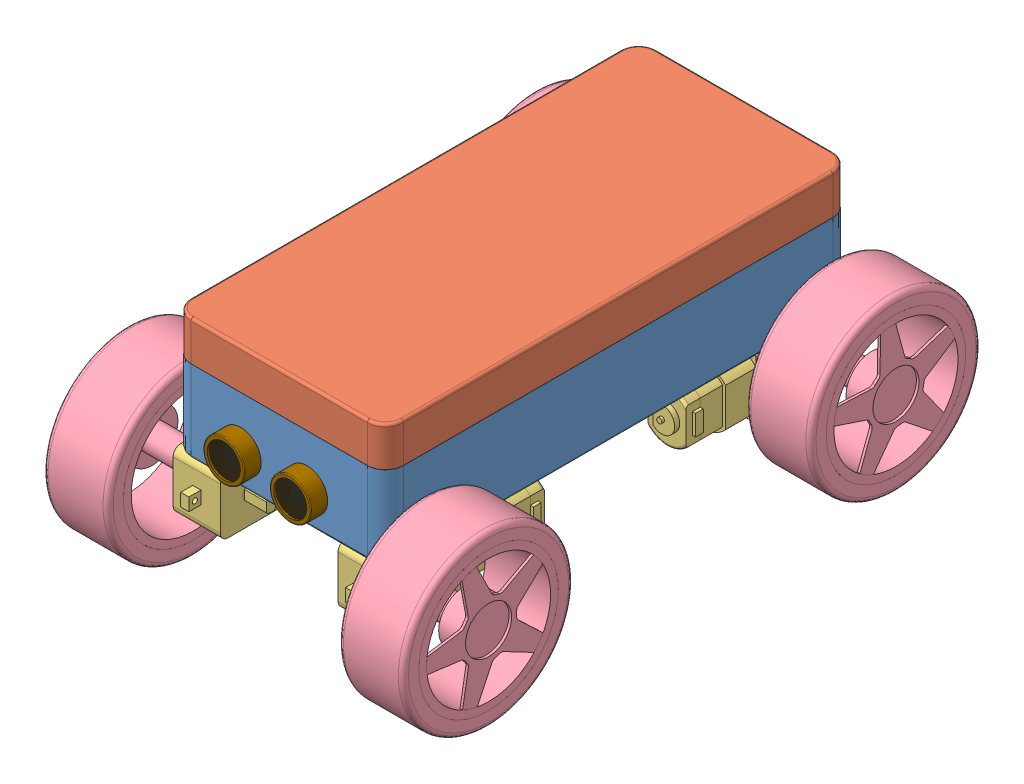
SolidWorks assembly Сборка1, configuration По умолчанию. Lengths in mm.
Overall size (141 100.91 238.58).
16 component instances, 10 part files, 33 mates.
Components (placement in the parent):
- Деталь1-1: Деталь1 [По умолчанию] at origin size (83 32 182)
- Деталь2-1: Деталь2 [По умолчанию] at (0 32.0442 0) x (1 0.000532 0) z (0 0 1) size (83 15.5 182)
- motor-1: motor [Predeterminado] at (-73.75 -11.35 -18.5) x (0 0 1) z (1 0 0) size (71.1 22.7 38)
- llanta-1: llanta [Predeterminado] at (-112 -11.35 -11.35) x (0 -0.972916 0.231159) z (-1 0 0) size (66.5 66.5 29)
- llanta-2: llanta [Predeterminado] at (29 -11.35 -11.35) x (0 0.314264 -0.949335) z (1 0 0) size (66.5 66.5 29)
- motor-2: motor [Predeterminado] at (-9.25 -11.35 -18.5) x (0 0 1) z (-1 0 0) size (71.1 22.7 38)
- motor-3: motor [Predeterminado] at (-9.25 -11.35 -163.5) x (0 0 -1) z (-1 0 0) size (71.1 22.7 38)
- llanta-3: llanta [Predeterminado] at (29 -11.35 -170.65) x (0 0.129067 -0.991636) z (1 0 0) size (66.5 66.5 29)
- motor-4: motor [Predeterminado] at (-73.75 -11.35 -163.5) x (0 0 -1) z (1 0 0) size (71.1 22.7 38)
- llanta-4: llanta [Predeterminado] at (-112 -11.35 -170.65) x (0 -0.02064 -0.999787) z (-1 0 0) size (66.5 66.5 29)
- Деталь3-1: Деталь3 [По умолчанию] at (-2 35 -85) x (0 1 0) z (0 0 1) size (33 61 32)
- Деталь4-1: Деталь4 [По умолчанию] at (-5.6654 2 -180) x (0 -1 0) z (0 0 -1) size (35 60 63)
- arduino-1: arduino [Valor predeterminado] at (-24.2753 10 -74.3614) size (45.18 17 17.78)
- hc05-1: hc05 [Varsayılan] at (-81 18.1 -175.0431) x (0 0 1) z (1 0 0) size (42.6 16.1 5.9)
- Sensor Ultrasonic-1: Sensor Ultrasonic [Predeterminado] at (-43.5678 12.17 -5.37) x (-1 0 0) z (0 0 1) size (45.42 26.14 17.7)
- L298N Dual H Bridge-1: L298N Dual H Bridge [Default] at (-29.5669 3.54 -42.6081) size (43.3 28.21 43.3)
Mates (geometry in assembly coordinates):
- Совпадение1: coincident aligned: line of Деталь1-1 through (-83 32 -175) axis (0 0 1); line of Деталь2-1 through (-83 32 -175) axis (0 0 1)
- Совпадение4: coincident: point of Деталь1-1; point of Деталь2-1
- Концентричный3: concentric anti-aligned: circle of motor-1; circle of llanta-1
- Совпадение5: coincident anti-aligned: plane of motor-1 through (-83 -19.7 -3) normal (-1 0 0); plane of llanta-1 through (-83 -11.35 -11.35) normal (1 0 0)
- Концентричный4: concentric anti-aligned: circle of llanta-2; circle of motor-2
- Совпадение6: coincident anti-aligned: plane of llanta-2 through (0 -11.35 -11.35) normal (-1 0 0); plane of motor-2 through (0 -3 -3) normal (1 0 0)
- Совпадение11: coincident anti-aligned: plane of Деталь1-1 through (-76 0 -7) normal (0 -1 0); plane of motor-2 through (0 0 -37) normal (0 1 0)
- Совпадение13: coincident aligned: plane of Деталь1-1 through (-7 32 0) normal (0 0 1); plane of motor-2 through (0 -19.7 0) normal (0 0 1)
- Совпадение14: coincident aligned: plane of Деталь1-1 through (0 32 -7) normal (1 0 0); plane of motor-2 through (0 -3 -3) normal (1 0 0)
- Совпадение15: coincident aligned: plane of Деталь1-1 through (-7 32 0) normal (0 0 1); plane of motor-1 through (-83 -3 0) normal (0 0 1)
- Совпадение16: coincident aligned: plane of Деталь1-1 through (-83 32 -7) normal (-1 0 0); plane of motor-1 through (-83 -19.7 -3) normal (-1 0 0)
- Совпадение17: coincident anti-aligned: plane of Деталь1-1 through (-76 0 -7) normal (0 -1 0); plane of motor-1 through (-83 0 -37) normal (0 1 0)
- Концентричный5: concentric anti-aligned: circle of motor-3; circle of llanta-3
- Совпадение18: coincident anti-aligned: plane of motor-3 through (0 -19.7 -179) normal (1 0 0); plane of llanta-3 through (0 -11.35 -170.65) normal (-1 0 0)
- Совпадение19: coincident aligned: plane of Деталь1-1 through (-7 32 -182) normal (0 0 -1); plane of motor-3 through (0 -3 -182) normal (0 0 -1)
- Совпадение20: coincident aligned: plane of Деталь1-1 through (0 32 -7) normal (1 0 0); plane of motor-3 through (0 -19.7 -179) normal (1 0 0)
- Совпадение21: coincident anti-aligned: plane of Деталь1-1 through (-76 0 -7) normal (0 -1 0); plane of motor-3 through (0 0 -145) normal (0 1 0)
- Концентричный6: concentric anti-aligned: circle of motor-4; circle of llanta-4
- Совпадение22: coincident anti-aligned: plane of motor-4 through (-83 -3 -179) normal (-1 0 0); plane of llanta-4 through (-83 -11.35 -170.65) normal (1 0 0)
- Совпадение32: coincident aligned: plane of Деталь1-1 through (-7 32 -182) normal (0 0 -1); plane of motor-4 through (-83 -19.7 -182) normal (0 0 -1)
- Совпадение33: coincident aligned: plane of Деталь1-1 through (-83 32 -7) normal (-1 0 0); plane of motor-4 through (-83 -3 -179) normal (-1 0 0)
- Совпадение34: coincident anti-aligned: plane of Деталь1-1 through (-76 0 -7) normal (0 -1 0); plane of motor-4 through (-83 0 -145) normal (0 1 0)
- Совпадение35: coincident anti-aligned: plane of Деталь1-1 through (-7 32 -180) normal (0 0 1); plane of Деталь4-1 through (-65.6654 4 -180) normal (0 0 -1)
- Совпадение36: coincident anti-aligned: plane of Деталь1-1 through (-76 2 -7) normal (0 1 0); plane of Деталь4-1 through (-65.6654 2 -178) normal (0 -1 0)
- Совпадение37: coincident anti-aligned: plane of Деталь3-1 through (-2 7 -112) normal (1 0 0); plane of Деталь1-1 through (-2 32 -7) normal (-1 0 0)
- Совпадение38: coincident anti-aligned: plane of Деталь1-1 through (-76 2 -7) normal (0 1 0); plane of Деталь3-1 through (-63 2 -85) normal (0 -1 0)
- Совпадение39: coincident anti-aligned: plane of Деталь3-1 through (-63 35 -117) normal (0 0 -1); plane of Деталь4-1 through (-65.6654 4 -117) normal (0 0 1)
- Совпадение40: coincident anti-aligned: plane of Деталь1-1 through (-7 32 -2) normal (0 0 -1); plane of Sensor Ultrasonic-1 through (-46.9778 4.05 -2) normal (0 0 1)
- Совпадение41: coincident anti-aligned: plane of Деталь1-1 through (-76 2 -7) normal (0 1 0); plane of Sensor Ultrasonic-1 through (-20.8578 2 -6.97) normal (0 -1 0)
- Совпадение42: coincident anti-aligned: plane of Деталь1-1 through (-76 2 -7) normal (0 1 0); plane of arduino-1 through (11.4947 2 -74.3614) normal (0 -1 0)
- Совпадение43: coincident anti-aligned: plane of Деталь1-1 through (-81 32 -7) normal (1 0 0); plane of hc05-1 through (-81 18.1 -175.0431) normal (-1 0 0)
- Совпадение44: coincident: plane of Деталь1-1 through (-76 2 -7) normal (0 1 0); line of hc05-1 through (-79.8 2 -137.5431) axis (0 0 -1)
- Совпадение45: coincident anti-aligned: plane of Деталь1-1 through (-76 2 -7) normal (0 1 0); plane of L298N Dual H Bridge-1 through (-29.5669 2 -42.6081) normal (0 -1 0)
